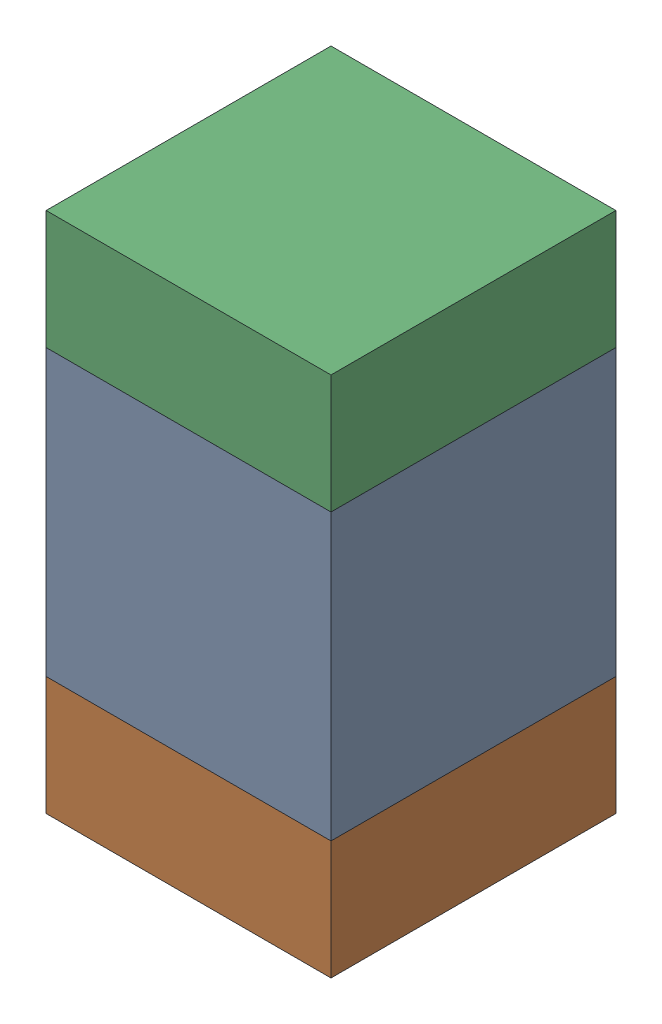
SolidWorks assembly C323_2PCB, configuration Default. Lengths in mm.
Overall size (0.6 1.1 0.6).
6 component instances, 2 part files, 0 mates.
Components (placement in the parent):
- 761606048-1: 761606048 [Default] at (140.8 87.1 -2.2638) size (0.6 0.6 0.6)
  - Extruded_9-1: Extruded_9 [Default] at origin size (0.6 0.6 0.6)
- 854785296-1: 854785296 [Default] at (140.8 86.675 -2.2638) size (0.6 0.25 0.6)
  - Extruded_10-1: Extruded_10 [Default] at origin size (0.6 0.25 0.6)
- 854785296-2: 854785296 [Default] at (140.8 87.525 -2.2638) size (0.6 0.25 0.6)
  - Extruded_10-1: Extruded_10 [Default] at origin size (0.6 0.25 0.6)
